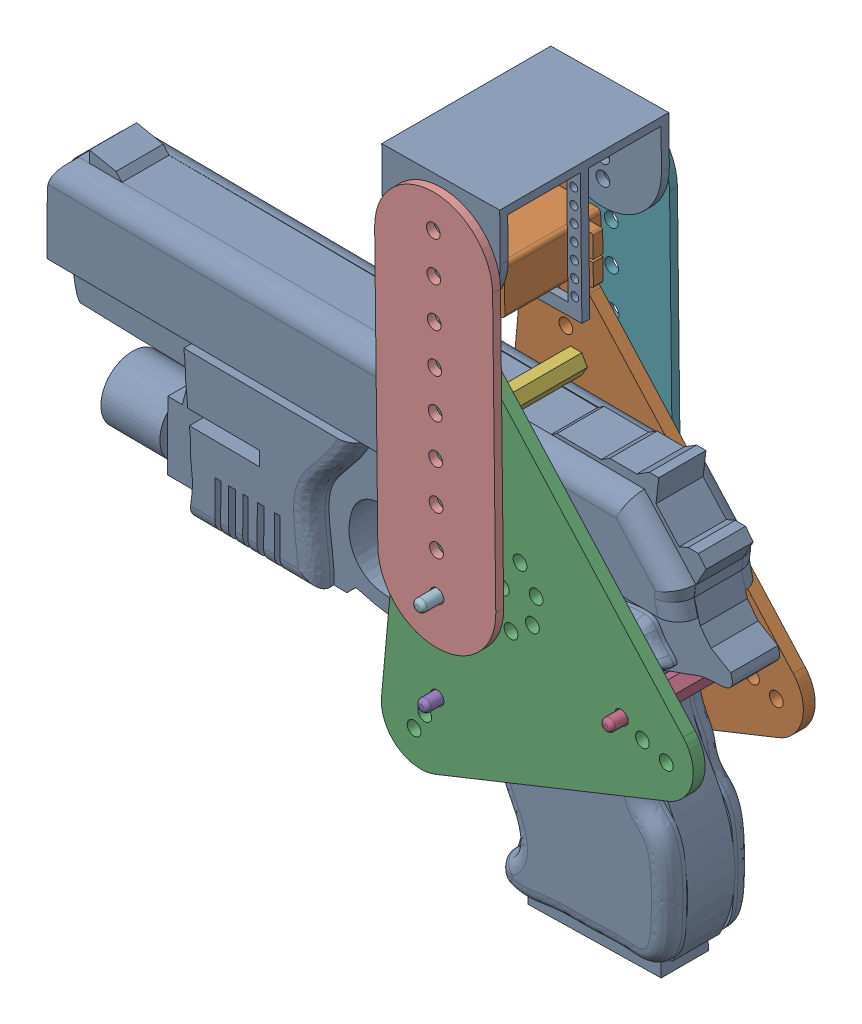
SolidWorks assembly Assem1, configuration Default. Lengths in mm.
Overall size (172.4 166.71 57).
12 component instances, 7 part files, 29 mates.
Components (placement in the parent):
- Pistol-1: Pistol [Default] at (-79.8161 -21.3808 38.3822) x (0.999965 -0.008364 0) z (0 0 1) size (170.2 110.84 23.85)
- Gun Holder-1: Gun Holder [Default] at (38.9508 46.7829 24.3822) x (0.999429 0.033791 0) z (0 0 1) size (80.08 101.07 3)
- Gun Holder-2: Gun Holder [Default] at (38.9508 46.7829 52.3822) x (0.999429 0.033791 0) z (0 0 1) size (80.08 101.07 3)
- Spacer25-1: Spacer25 [Default] at (74.0122 39.242 27.3822) x (1 0 0) z (0 -1 0) size (5.42 32 5.69)
- Spacer25-2: Spacer25 [Default] at (27.148 20.1176 27.3822) x (1 0 0) z (0 -1 0) size (5.42 32 5.69)
- Spacer25-3: Spacer25 [Default] at (34.4852 84.0611 27.3822) x (0.161693 -0.986841 0) z (-0.986841 -0.161693 0) size (5.42 32 5.69)
- GunJoint1-1: GunJoint1 [Default] at (35.0779 54.0983 16.3822) x (0.999934 0.011519 0) z (0 0 1) size (30 100 2)
- Spacer6-1: Spacer6 [Default] at (35.1185 50.5755 24.3822) x (-0.923728 -0.383049 0) z (0.383049 -0.923728 0) size (5.42 13 5.69)
- GunJoint1-2: GunJoint1 [Default] at (35.0779 54.0983 61.3822) x (0.999934 0.011519 0) z (0 0 1) size (30 100 2)
- Spacer6-2: Spacer6 [Default] at (35.1185 50.5755 55.3822) x (0.928642 0.370977 0) z (0.370977 -0.928642 0) size (5.42 13 5.69)
- GunJoint2-1: GunJoint2 [Default] at (34.073 141.3311 39.8822) x (0 0 1) z (0.999934 0.011519 0) size (43 35 30)
- ServoSmall-1: ServoSmall [Default] at (34.3247 119.4757 56.8822) x (-0.999934 -0.011519 0) z (0.011519 -0.999934 0) size (32 32 12)
Mates (geometry in assembly coordinates):
- Coincident1: coincident anti-aligned: plane of Gun Holder-1 through (82.2958 36.0796 27.3822) normal (0 0 1); plane of Spacer25-3 through (34.4852 84.0611 27.3822) normal (0 0 -1)
- Coincident2: coincident anti-aligned: plane of Gun Holder-1 through (82.2958 36.0796 27.3822) normal (0 0 1); plane of Spacer25-1 through (74.0122 39.242 27.3822) normal (0 0 -1)
- Coincident3: coincident anti-aligned: plane of Gun Holder-1 through (82.2958 36.0796 27.3822) normal (0 0 1); plane of Spacer25-2 through (27.148 20.1176 27.3822) normal (0 0 -1)
- Coincident4: coincident anti-aligned: plane of Pistol-1 through (41.7496 -20.3069 27.3822) normal (0 0 -1); plane of Gun Holder-1 through (82.2958 36.0796 27.3822) normal (0 0 1)
- Concentric1: concentric aligned: circle of Gun Holder-1; circle of Spacer25-1
- Concentric2: concentric aligned: circle of Gun Holder-1; circle of Spacer25-3
- Concentric3: concentric aligned: circle of Gun Holder-1; circle of Spacer25-2
- Concentric4: concentric anti-aligned: cylinder of Gun Holder-2 through (27.148 20.1176 55.3822) axis (0 0 -1) radius 1.75; circle of Spacer25-2
- Concentric6: concentric anti-aligned: circle of Gun Holder-2; circle of Spacer25-1
- Coincident5: coincident anti-aligned: plane of Gun Holder-2 through (82.2958 36.0796 52.3822) normal (0 0 -1); plane of Spacer25-1 through (74.0122 39.242 52.3822) normal (0 0 1)
- Coincident6: coincident anti-aligned: plane of Pistol-1 through (44.9544 81.4534 44.3822) normal (0.010268 0.999947 0); plane of Spacer25-3 through (33.0162 81.576 52.3822) normal (-0.010268 -0.999947 0)
- Parallel1: parallel: line of assembly; face of Pistol-1; line of Spacer25-1 through (74.5081 42.0858 52.3822) axis (0 0 -1)
- Parallel3: parallel anti-aligned: line of Pistol-1 through (66.6593 76.4999 27.3822) axis (0.669266 -0.743023 0); line of Gun Holder-1 through (89.7261 42.7723 27.3822) axis (-0.669266 0.743023 0)
- Distance1: distance = 9.0521 mm: line of Spacer25-3 through (35.9028 81.5464 52.3822) axis (0 0 -1); line of Pistol-1 through (44.9544 81.4534 44.3822) axis (0 0 -1)
- Concentric7: concentric anti-aligned: circle of Gun Holder-1; circle of Spacer6-1
- Coincident9: coincident anti-aligned: plane of Gun Holder-1 through (82.2958 36.0796 24.3822) normal (0 0 -1); plane of Spacer6-1 through (35.1185 50.5755 24.3822) normal (0 0 1)
- Coincident10: coincident anti-aligned: plane of GunJoint1-1 through (35.0779 54.0983 18.3822) normal (0 0 1); plane of Spacer6-1 through (35.1185 50.5755 18.3822) normal (0 0 -1)
- Concentric8: concentric anti-aligned: circle of GunJoint1-1; circle of Spacer6-1
- Concentric10: concentric aligned: circle of Gun Holder-2; circle of Spacer6-2
- Coincident12: coincident anti-aligned: plane of Gun Holder-2 through (82.2958 36.0796 55.3822) normal (0 0 1); plane of Spacer6-2 through (35.1185 50.5755 55.3822) normal (0 0 -1)
- Concentric11: concentric aligned: circle of GunJoint1-2; circle of Spacer6-2
- Coincident13: coincident anti-aligned: plane of GunJoint1-2 through (35.0779 54.0983 61.3822) normal (0 0 -1); plane of Spacer6-2 through (35.1185 50.5755 61.3822) normal (0 0 1)
- Coincident14: coincident anti-aligned: plane of GunJoint1-2 through (35.0779 54.0983 61.3822) normal (0 0 -1); plane of GunJoint2-1 through (19.097 139.1585 61.3822) normal (0 0 1)
- Coincident15: coincident anti-aligned: circle of GunJoint1-2; circle of GunJoint2-1
- Coincident16: coincident anti-aligned: circle of GunJoint1-2; circle of GunJoint2-1
- Coincident17: coincident anti-aligned: circle of GunJoint1-1; circle of GunJoint2-1
- Coincident18: coincident anti-aligned: plane of GunJoint2-1 through (34.4416 109.3332 38.8822) normal (0 0 -1); plane of ServoSmall-1 through (34.3247 119.4757 38.8822) normal (0 0 1)
- Parallel5: parallel anti-aligned: plane of GunJoint2-1 through (34.096 139.3313 39.8822) normal (0.011519 -0.999934 0); plane of ServoSmall-1 through (45.7549 125.6078 38.8822) normal (-0.011519 0.999934 0)
- Coincident20: coincident anti-aligned: plane of GunJoint2-1 through (45.9408 109.4657 39.8822) normal (-0.999934 -0.011519 0); plane of ServoSmall-1 through (45.7549 125.6078 38.8822) normal (0.999934 0.011519 0)
